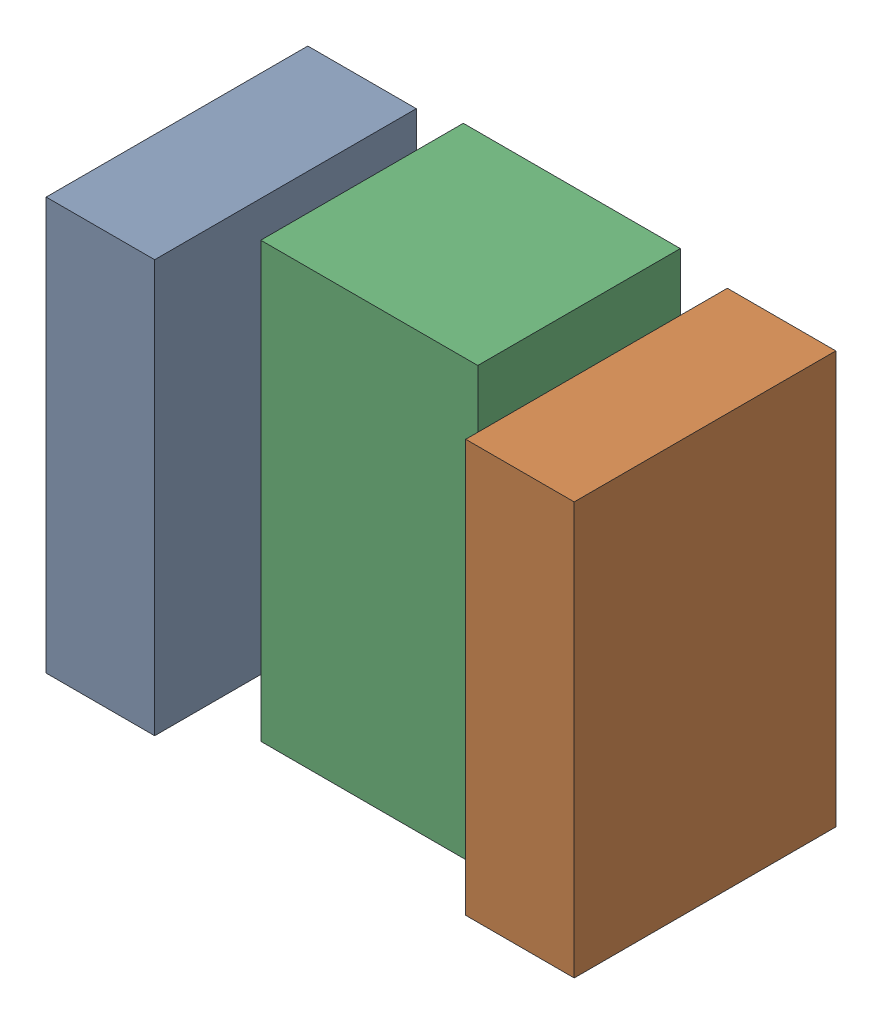
SolidWorks assembly C7_Motor_7Kanaloa_v2.0.0_Motor, configuration Default. Lengths in mm.
Overall size (3.65 3 1.81).
6 component instances, 2 part files, 0 mates.
Components (placement in the parent):
- 334788400-1: 334788400 [Default] at (102.134 139.192 0) size (0.75 2.85 1.81)
  - Extruded_5-1: Extruded_5 [Default] at origin size (0.75 2.85 1.81)
- 334788400-2: 334788400 [Default] at (105.034 139.192 0) size (0.75 2.85 1.81)
  - Extruded_5-1: Extruded_5 [Default] at origin size (0.75 2.85 1.81)
- 334788656-1: 334788656 [Default] at (103.584 139.192 0) size (1.5 3 1.4)
  - Extruded_1-1: Extruded_1 [Default] at origin size (1.5 3 1.4)
